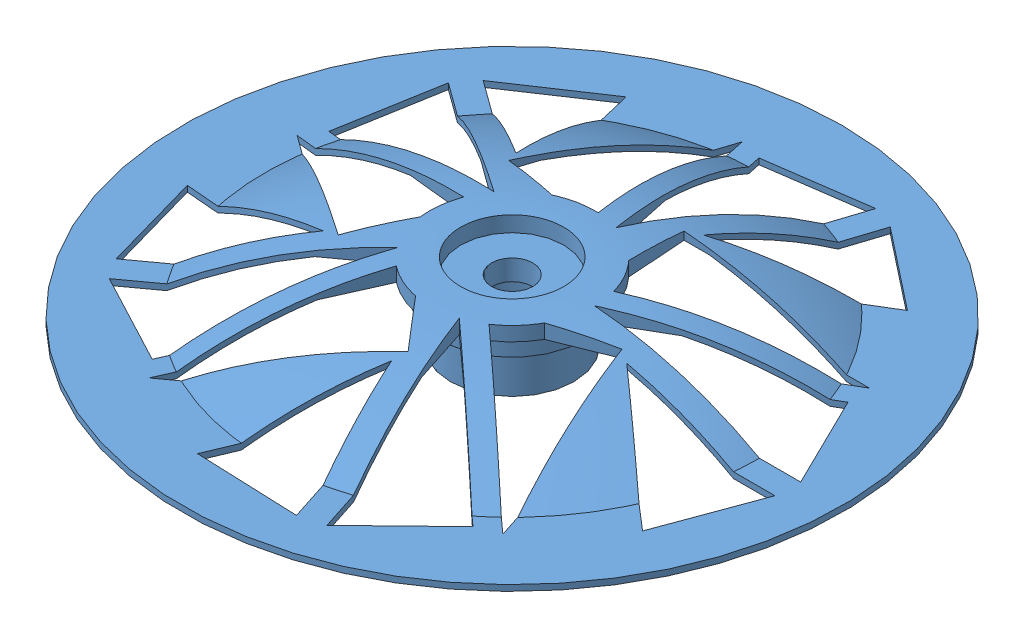
SolidWorks assembly pedal gear, configuration Default. Lengths in mm.
Overall size (203.2 31.47 203.2).
2 component instances, 2 part files, 2 mates.
Components (placement in the parent):
- g_plate-1: g_plate [Default] at (-36.8445 -0.9774 12.0174) size (203.2 31.47 203.2)
- spur gear_ai-1: spur gear_ai [PreviewCfg] at (-36.8445 18.0726 12.0174) x (0 -1 0) z (0 0 1) size (12.7 86.43 86.43)
Mates (geometry in assembly coordinates):
- Concentric1: concentric anti-aligned: cylinder of g_plate-1 through (-36.8445 -0.9774 12.0174) axis (0 -1 0) radius 101.6; cylinder of spur gear_ai-1 through (-36.8445 -7.3274 12.0174) axis (0 1 0) radius 9.525
- Coincident1: coincident aligned: plane of g_plate-1 through (64.7555 5.3726 12.0174) normal (0 -1 0); plane of spur gear_ai-1 through (-36.8445 5.3726 12.0174) normal (0 -1 0)
